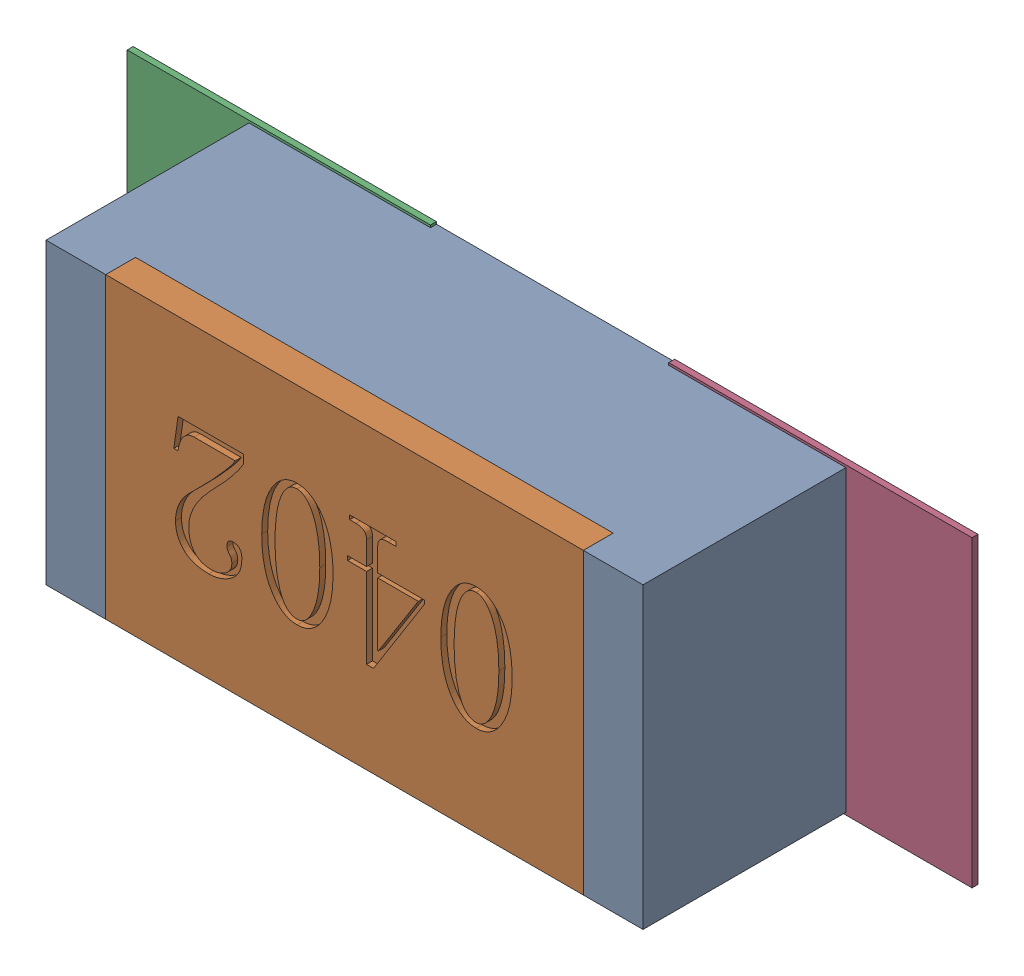
SolidWorks assembly R140, configuration Défaut. Lengths in mm.
Overall size (1.42 0.51 0.35).
5 component instances, 2 part files, 0 mates.
Components (placement in the parent):
- R0402-1: R0402 [Défaut] at (12.2865 -28.8035 0) x (-1 0 0) z (0 0 1) size (1 0.5 0.35)
- 6504207776-1: 6504207776 [Défaut] at (11.8365 -28.8036 0) size (0.51 0.51 0.01)
  - Extruded-1: Extruded [Défaut] at origin size (0.51 0.51 0.01)
- 6504207776-2: 6504207776 [Défaut] at (12.7436 -28.8036 0) size (0.51 0.51 0.01)
  - Extruded-1: Extruded [Défaut] at origin size (0.51 0.51 0.01)
